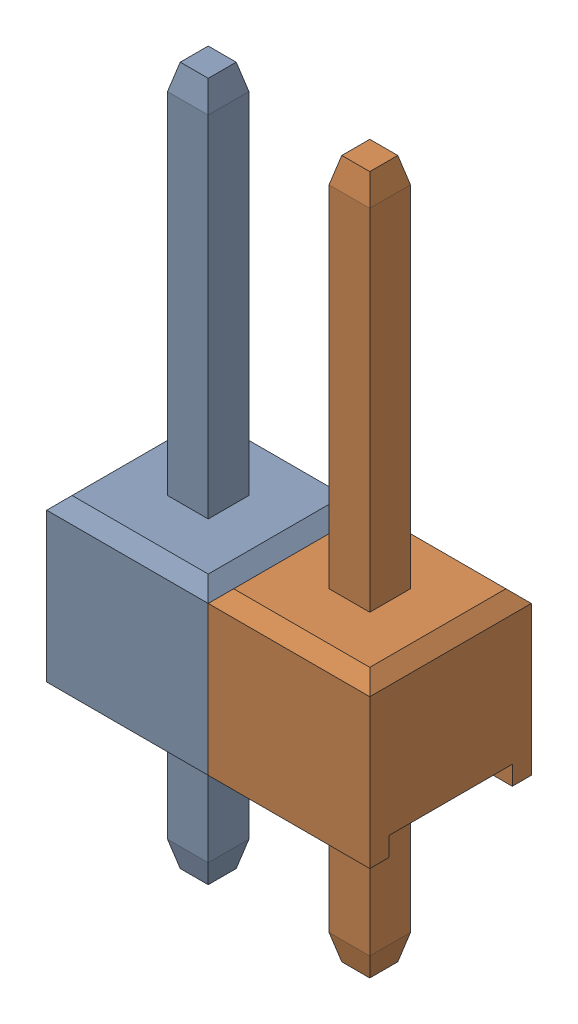
SolidWorks assembly User Library-BluePill_User_Library-Header3x2_100_TH_User_Library-Header1x2, configuration Default. Lengths in mm.
Overall size (5.08 10.98 2.54).
2 component instances, 1 part files, 0 mates.
Components (placement in the parent):
- User Library-BluePill_User_Library-Header3x2_100_TH_User_Library-Header1x2_Header1_1-1: User Library-BluePill_User_Library-Header3x2_100_TH_User_Library-Header1x2_Header1_1 [Default] at (4.4052 8.1155 -11.7669) size (2.54 10.98 2.54)
- User Library-BluePill_User_Library-Header3x2_100_TH_User_Library-Header1x2_Header1_1-2: User Library-BluePill_User_Library-Header3x2_100_TH_User_Library-Header1x2_Header1_1 [Default] at (6.9452 8.1155 -11.7669) size (2.54 10.98 2.54)
